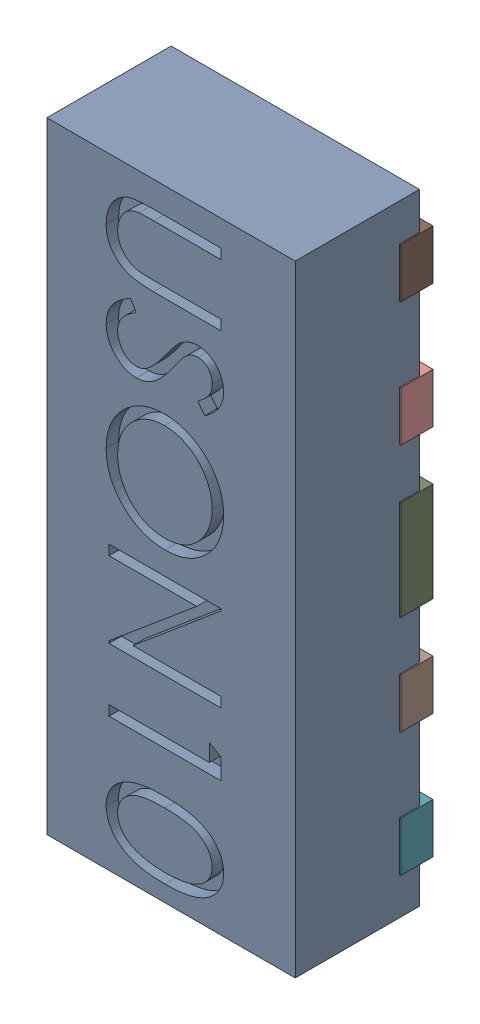
SolidWorks assembly D31, configuration Défaut. Lengths in mm.
Overall size (1.01 2.5 0.55).
12 component instances, 5 part files, 0 mates.
Components (placement in the parent):
- UDFN10-1: UDFN10 [Défaut] at (73.7018 -29.2059 -0.9099) x (0 -1 0) z (-1 0 0) size (2.5 0.55 1.01)
  - User Library-UDFN10_Body-1: User Library-UDFN10_Body [Défaut] at (1.0785 0.9721 1.8983) size (2.5 0.5 1)
  - User Library-UDFN10_Pin1-1: User Library-UDFN10_Pin1 [Défaut] at (0.0785 1.0521 2.2208) x (0 0 -1) z (-1 0 0) size (0.37 0.13 0.2)
  - User Library-UDFN10_Pin2-1: User Library-UDFN10_Pin2 [Défaut] at (0.5785 1.0521 2.2208) x (0 0 1) z (1 0 0) size (0.37 0.13 0.2)
  - User Library-UDFN10_Pin4-1: User Library-UDFN10_Pin4 [Défaut] at (1.0785 0.9221 2.2208) x (0 0 1) z (-1 0 0) size (0.49 0.13 0.4)
  - User Library-UDFN10_Pin2-2: User Library-UDFN10_Pin2 [Défaut] at (1.5785 0.9221 2.2208) x (0 0 1) z (-1 0 0) size (0.37 0.13 0.2)
  - User Library-UDFN10_Pin2-3: User Library-UDFN10_Pin2 [Défaut] at (2.0785 0.9221 2.2208) x (0 0 1) z (-1 0 0) size (0.37 0.13 0.2)
  - User Library-UDFN10_Pin2-4: User Library-UDFN10_Pin2 [Défaut] at (2.0785 0.9221 1.5758) x (0 0 -1) z (1 0 0) size (0.37 0.13 0.2)
  - User Library-UDFN10_Pin2-5: User Library-UDFN10_Pin2 [Défaut] at (1.5785 0.9221 1.5758) x (0 0 -1) z (1 0 0) size (0.37 0.13 0.2)
  - User Library-UDFN10_Pin3-1: User Library-UDFN10_Pin3 [Défaut] at (1.0785 0.9221 1.5758) x (0 0 1) z (-1 0 0) size (0.37 0.13 0.4)
  - User Library-UDFN10_Pin2-6: User Library-UDFN10_Pin2 [Défaut] at (0.5785 0.9221 1.5758) x (0 0 -1) z (1 0 0) size (0.37 0.13 0.2)
  - User Library-UDFN10_Pin2-7: User Library-UDFN10_Pin2 [Défaut] at (0.0785 0.9221 1.5758) x (0 0 -1) z (1 0 0) size (0.37 0.13 0.2)
